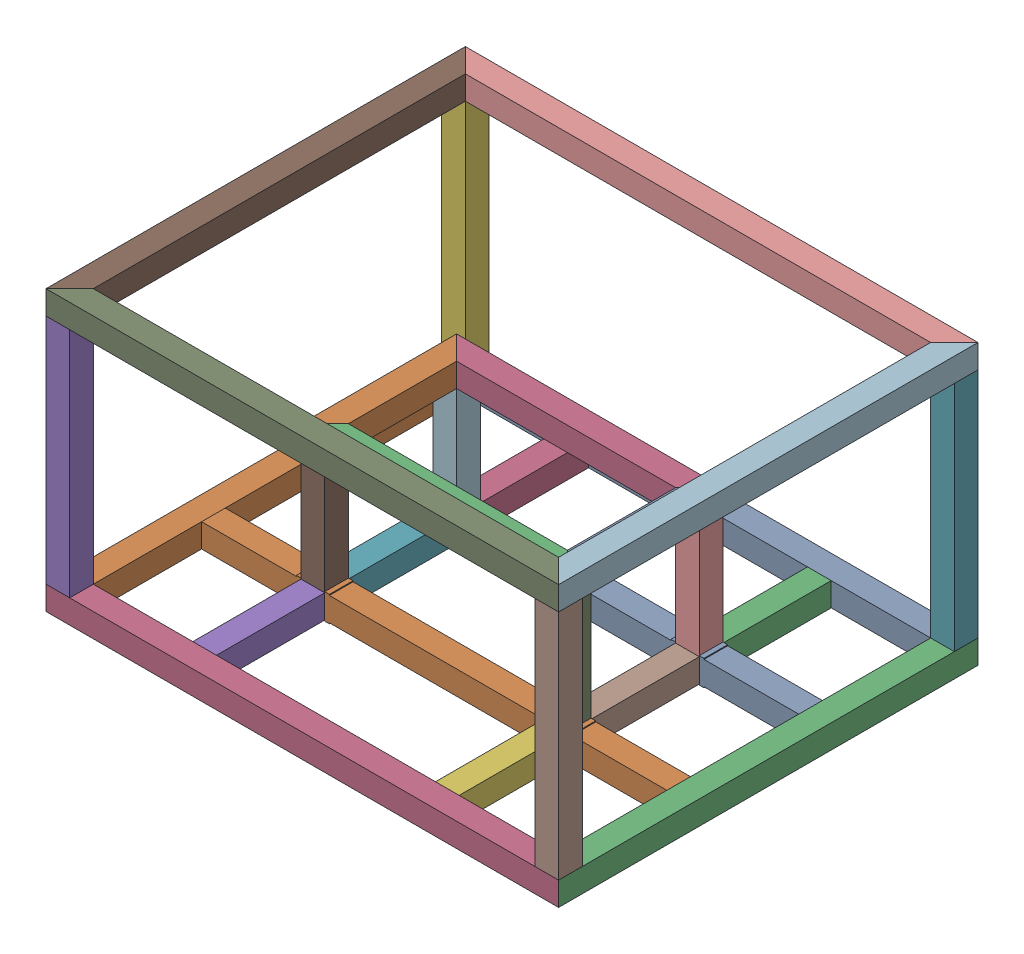
SolidWorks assembly AGV_ensamble, configuration Predeterminado. Lengths in mm.
Overall size (550 301 450).
28 component instances, 9 part files, 72 mates.
Components (placement in the parent):
- perfil_angulo45_550-2: perfil_angulo45_550 [Predeterminado] x (-1 0 0) z (0 0 -1) size (550 25.4 25.4)
- perfil_angulo45_450-1: perfil_angulo45_450 [Predeterminado] at (-550 0 0) x (0 0 1) z (-1 0 0) size (450 25.4 25.4)
- perfil_angulo45_450-2: perfil_angulo45_450 [Predeterminado] at (0 0 450) x (0 0 -1) z (1 0 0) size (450 25.4 25.4)
- perfil_angulo45_550-3: perfil_angulo45_550 [Predeterminado] at (-550 0 450) size (550 25.4 25.4)
- perfil_sencillo_250-1: perfil_sencillo_250 [Predeterminado] at (-524.6 25.4 450) x (0 0 -1) z (1 0 0) size (25.4 249.2 25.4)
- perfil_sencillo_250-2: perfil_sencillo_250 [Predeterminado] at (-524.6 25.4 25.4) x (0 0 -1) z (1 0 0) size (25.4 249.2 25.4)
- perfil_sencillo_250-3: perfil_sencillo_250 [Predeterminado] at (0 25.4 25.4) x (0 0 -1) z (1 0 0) size (25.4 249.2 25.4)
- perfil_sencillo_250-4: perfil_sencillo_250 [Predeterminado] at (-25.4 25.4 450) size (25.4 249.2 25.4)
- perfil_angulo45_550-4: perfil_angulo45_550 [Predeterminado] at (-550 274.6 450) size (550 25.4 25.4)
- perfil_angulo45_550-5: perfil_angulo45_550 [Predeterminado] at (-550 300 0) x (1 0 0) z (0 0 -1) size (550 25.4 25.4)
- perfil_angulo45_450-3: perfil_angulo45_450 [Predeterminado] at (-550 300 450) x (0 0 -1) z (-1 0 0) size (450 25.4 25.4)
- perfil_angulo45_450-4: perfil_angulo45_450 [Predeterminado] at (0 300 0) x (0 0 1) z (1 0 0) size (450 25.4 25.4)
- perfil_sencillo_500-1: perfil_sencillo_500 [Predeterminado] at (-524.6 0 166.93) x (0 0 -1) z (0 -1 0) size (25.4 499.2 27.4)
- perfil_sencillo_500-2: perfil_sencillo_500 [Predeterminado] at (-25.4 25.4 308.47) x (0 0 -1) z (0 1 0) size (25.4 499.2 27.4)
- perfil_sencillo_116-1: perfil_sencillo_116 [Predeterminado] at (-132.1 0 25.4) x (0 1 0) z (1 0 0) size (25.4 116.13 25.4)
- perfil_sencillo_116-2: perfil_sencillo_116 [Predeterminado] at (-417.9 0 25.4) x (1 0 0) z (0 -1 0) size (25.4 116.13 25.4)
- perfil_sencillo_116-4: perfil_sencillo_116 [Predeterminado] at (-417.9 25.4 424.6) x (1 0 0) z (0 1 0) size (25.4 116.13 25.4)
- perfil_sencillo_116-6: perfil_sencillo_116 [Predeterminado] at (-157.5 25.4 424.6) x (1 0 0) z (0 1 0) size (25.4 116.13 25.4)
- perfil_sencillo_11614-1: perfil_sencillo_11614 [Predeterminado] at (-417.9 25.4 283.07) x (1 0 0) z (0 1 0) size (25.4 116.14 25.4)
- perfil_sencillo_11614-2: perfil_sencillo_11614 [Predeterminado] at (-132.1 25.4 283.07) x (0 -1 0) z (1 0 0) size (25.4 116.14 25.4)
- perfil_sencillo_119-1: perfil_sencillo_119 [Predeterminado] at (-132.1 144.4 308.47) x (0 -1 0) z (1 0 0) size (119 25.4 25.4)
- perfil_sencillo_119-2: perfil_sencillo_119 [Predeterminado] at (-132.1 144.4 166.93) x (0 -1 0) z (1 0 0) size (119 25.4 25.4)
- perfil_sencillo_119-3: perfil_sencillo_119 [Predeterminado] at (-417.9 144.4 283.07) x (0 -1 0) z (-1 0 0) size (119 25.4 25.4)
- perfil_sencillo_119-4: perfil_sencillo_119 [Predeterminado] at (-417.9 144.4 141.53) x (0 -1 0) z (-1 0 0) size (119 25.4 25.4)
- perfil_angulo45_166_94-1: perfil_angulo45_166_94 [Predeterminado] at (-157.5 169.8 141.53) x (0 -1 0) z (-1 0 0) size (25.4 166.94 25.4)
- perfil_angulo45_166_94-2: perfil_angulo45_166_94 [Predeterminado] at (-392.5 144.4 141.53) x (0 1 0) z (1 0 0) size (25.4 166.94 25.4)
- perfil_angulo45_285_8-1: perfil_angulo45_285_8 [Predeterminado] at (-417.9 144.4 308.47) size (285.8 25.4 25.4)
- perfil_angulo45_285_8-2: perfil_angulo45_285_8 [Predeterminado] at (-132.1 144.4 141.53) x (-1 0 0) z (0 0 -1) size (285.8 25.4 25.4)
Mates (geometry in assembly coordinates):
- Coincident2: coincident anti-aligned: plane of perfil_angulo45_550-2 through (-550 0 0) normal (-0.707107 0 0.707107); plane of perfil_angulo45_450-1 through (-550 0 0) normal (0.707107 0 -0.707107)
- Coincident3: coincident: point of perfil_angulo45_550-2; unknown of perfil_angulo45_450-1
- Parallel5: parallel anti-aligned: plane of perfil_angulo45_450-1 through (-550 0 450) normal (0.707107 0 0.707107); plane of perfil_angulo45_550-3 through (-550 0 450) normal (-0.707107 0 -0.707107)
- Coincident13: coincident aligned: line of perfil_angulo45_450-1 through (-550 25.4 450) axis (0 -1 0); line of perfil_angulo45_550-3 through (-550 25.4 450) axis (0 -1 0)
- Coincident14: coincident anti-aligned: line of perfil_angulo45_450-1 through (-524.6 25.4 424.6) axis (-0.707107 0 0.707107); line of perfil_angulo45_550-3 through (-550 25.4 450) axis (0.707107 0 -0.707107)
- Coincident15: coincident anti-aligned: line of perfil_angulo45_550-2 through (0 25.4 0) axis (-0.707107 0 0.707107); line of perfil_angulo45_450-2 through (-25.4 25.4 25.4) axis (0.707107 0 -0.707107)
- Parallel6: parallel anti-aligned: plane of perfil_angulo45_550-2 through (0 0 0) normal (0.707107 0 0.707107); plane of perfil_angulo45_450-2 through (0 0 0) normal (-0.707107 0 -0.707107)
- Coincident17: coincident aligned: line of perfil_angulo45_550-2 through (-25.4 0 25.4) axis (0 1 0); line of perfil_angulo45_450-2 through (-25.4 0 25.4) axis (0 1 0)
- Coincident24: coincident aligned: line of perfil_angulo45_550-3 through (-550 25.4 450) axis (1 0 0); line of perfil_sencillo_250-1 through (-550 25.4 450) axis (1 0 0)
- Coincident25: coincident aligned: line of perfil_angulo45_450-1 through (-550 25.4 0) axis (0 0 1); line of perfil_sencillo_250-1 through (-550 25.4 424.6) axis (0 0 1)
- Coincident26: coincident aligned: line of perfil_angulo45_450-2 through (0 25.4 450) axis (0 -1 0); line of perfil_angulo45_550-3 through (0 25.4 450) axis (0 -1 0)
- Coincident27: coincident aligned: line of perfil_angulo45_550-2 through (0 25.4 0) axis (-1 0 0); line of perfil_sencillo_250-2 through (-524.6 25.4 0) axis (-1 0 0)
- Coincident28: coincident aligned: line of perfil_angulo45_450-1 through (-550 25.4 0) axis (0 0 1); line of perfil_sencillo_250-2 through (-550 25.4 0) axis (0 0 1)
- Coincident29: coincident aligned: line of perfil_angulo45_550-2 through (0 25.4 0) axis (-1 0 0); line of perfil_sencillo_250-3 through (0 25.4 0) axis (-1 0 0)
- Coincident30: coincident aligned: line of perfil_angulo45_450-2 through (0 25.4 450) axis (0 0 -1); line of perfil_sencillo_250-3 through (0 25.4 25.4) axis (0 0 -1)
- Coincident31: coincident aligned: line of perfil_angulo45_450-2 through (0 25.4 450) axis (0 0 -1); line of perfil_sencillo_250-4 through (0 25.4 450) axis (0 0 -1)
- Coincident32: coincident aligned: line of perfil_angulo45_550-3 through (-550 25.4 450) axis (1 0 0); line of perfil_sencillo_250-4 through (-25.4 25.4 450) axis (1 0 0)
- Coincident37: coincident: point of perfil_sencillo_250-4; point of perfil_angulo45_450-4
- Coincident38: coincident anti-aligned: line of perfil_sencillo_250-4 through (0 274.6 450) axis (0 0 -1); line of perfil_angulo45_450-4 through (0 274.6 0) axis (0 0 1)
- Coincident39: coincident: point of perfil_sencillo_250-4; point of perfil_angulo45_450-4
- Coincident40: coincident: point of perfil_sencillo_250-1; point of perfil_angulo45_550-4
- Coincident41: coincident: point of perfil_sencillo_250-4; point of perfil_angulo45_550-4
- Coincident42: coincident: point of perfil_sencillo_250-1; point of perfil_angulo45_550-4
- Coincident46: coincident: point of perfil_angulo45_550-5; point of perfil_angulo45_450-4
- Coincident47: coincident anti-aligned: line of perfil_sencillo_250-3 through (0 274.6 0) axis (-1 0 0); line of perfil_angulo45_550-5 through (-550 274.6 0) axis (1 0 0)
- Coincident48: coincident: point of perfil_sencillo_250-3; point of perfil_angulo45_550-5
- Coincident49: coincident: point of perfil_sencillo_250-1; point of perfil_angulo45_450-3
- Coincident50: coincident: point of perfil_angulo45_550-5; point of perfil_angulo45_450-3
- Coincident51: coincident aligned: line of perfil_angulo45_550-5 through (-524.6 300 25.4) axis (0 -1 0); line of perfil_angulo45_450-3 through (-524.6 300 25.4) axis (0 -1 0)
- Coincident55: coincident anti-aligned: line of perfil_angulo45_450-1 through (-524.6 25.4 424.6) axis (0 0 -1); line of perfil_sencillo_500-1 through (-524.6 25.4 141.53) axis (0 0 1)
- Coincident56: coincident aligned: line of perfil_angulo45_450-2 through (-25.4 25.4 25.4) axis (0 0 1); line of perfil_sencillo_500-1 through (-25.4 25.4 141.53) axis (0 0 1)
- Coincident57: coincident aligned: line of perfil_angulo45_450-1 through (-524.6 25.4 424.6) axis (0 0 -1); line of perfil_sencillo_500-2 through (-524.6 25.4 308.47) axis (0 0 -1)
- Coincident58: coincident anti-aligned: line of perfil_angulo45_450-2 through (-25.4 25.4 25.4) axis (0 0 1); line of perfil_sencillo_500-2 through (-25.4 25.4 308.47) axis (0 0 -1)
- Coincident61: coincident anti-aligned: line of perfil_angulo45_550-2 through (-524.6 25.4 25.4) axis (1 0 0); line of perfil_sencillo_116-2 through (-392.5 25.4 25.4) axis (-1 0 0)
- Coincident65: coincident anti-aligned: line of perfil_angulo45_550-2 through (-524.6 25.4 25.4) axis (1 0 0); line of perfil_sencillo_116-1 through (-132.1 25.4 25.4) axis (-1 0 0)
- Coincident66: coincident: unknown of perfil_angulo45_450-2
- Parallel9: parallel: line of perfil_angulo45_550-2 through (-1.2 1.2 1.2) axis (-1 0 0)
- Coincident68: coincident: line of perfil_angulo45_550-2 through (0 0 0) axis (-1 0 0)
- Coincident70: coincident: line of perfil_angulo45_550-3 through (-25.4 0 424.6) axis (-1 0 0)
- Coincident82: coincident anti-aligned: line of perfil_angulo45_550-3 through (-25.4 25.4 424.6) axis (-1 0 0); line of perfil_sencillo_116-4 through (-417.9 25.4 424.6) axis (1 0 0)
- Coincident84: coincident aligned: line of perfil_angulo45_550-3 through (-25.4 0 424.6) axis (-1 0 0); line of perfil_sencillo_116-6 through (-132.1 0 424.6) axis (-1 0 0)
- Coincident86: coincident aligned: line of perfil_sencillo_500-1 through (-25.4 25.4 141.53) axis (-1 0 0); line of perfil_sencillo_116-2 through (-392.5 25.4 141.53) axis (-1 0 0)
- Coincident87: coincident aligned: line of perfil_sencillo_500-1 through (-25.4 25.4 141.53) axis (-1 0 0); line of perfil_sencillo_116-1 through (-132.1 25.4 141.53) axis (-1 0 0)
- Coincident88: coincident aligned: line of perfil_sencillo_500-2 through (-524.6 25.4 308.47) axis (1 0 0); line of perfil_sencillo_116-4 through (-417.9 25.4 308.47) axis (1 0 0)
- Coincident89: coincident aligned: line of perfil_sencillo_500-2 through (-524.6 25.4 308.47) axis (1 0 0); line of perfil_sencillo_116-6 through (-157.5 25.4 308.47) axis (1 0 0)
- Coincident90: coincident aligned: line of perfil_sencillo_500-2 through (-524.6 25.4 283.07) axis (1 0 0); line of perfil_sencillo_11614-1 through (-417.9 25.4 283.07) axis (1 0 0)
- Coincident91: coincident anti-aligned: line of perfil_sencillo_500-1 through (-25.4 25.4 166.93) axis (-1 0 0); line of perfil_sencillo_11614-1 through (-417.9 25.4 166.93) axis (1 0 0)
- Coincident97: coincident aligned: line of perfil_sencillo_500-2 through (-524.6 25.4 283.07) axis (1 0 0); line of perfil_sencillo_11614-2 through (-157.5 25.4 283.07) axis (1 0 0)
- Coincident98: coincident anti-aligned: line of perfil_sencillo_500-1 through (-25.4 25.4 166.93) axis (-1 0 0); line of perfil_sencillo_11614-2 through (-157.5 25.4 166.93) axis (1 0 0)
- Coincident101: coincident: point of perfil_sencillo_500-2; point of perfil_sencillo_116-6
- Coincident102: coincident: point of perfil_sencillo_500-2; point of perfil_sencillo_116-4
- Coincident103: coincident: point of perfil_sencillo_500-2; point of perfil_sencillo_11614-1
- Coincident104: coincident: point of perfil_sencillo_500-1; point of perfil_sencillo_116-2
- Coincident105: coincident: point of perfil_sencillo_500-2; point of perfil_sencillo_11614-2
- Coincident106: coincident: point of perfil_sencillo_500-1; point of perfil_sencillo_116-1
- Coincident139: coincident anti-aligned: plane of perfil_sencillo_500-1 through (-25.4 25.4 141.53) normal (0 1 0); plane of perfil_angulo45_94_6-2 through (-132.1 25.4 141.53) normal (0 -1 0)
- Coincident140: coincident aligned: line of perfil_sencillo_500-1 through (-25.4 25.4 141.53) axis (-1 0 0); line of perfil_angulo45_94_6-2 through (-132.1 25.4 141.53) axis (-1 0 0)
- Coincident141: coincident anti-aligned: line of perfil_sencillo_500-1 through (-157.5 25.4 166.93) axis (0 0 -1); line of perfil_angulo45_94_6-2 through (-157.5 25.4 141.53) axis (0 0 1)
- Coincident142: coincident anti-aligned: line of perfil_sencillo_500-2 through (-127.1 25.4 308.47) axis (1 0 0); line of perfil_sencillo_119-1 through (-132.1 25.4 308.47) axis (-1 0 0)
- Coincident143: coincident anti-aligned: line of perfil_sencillo_500-2 through (-157.5 25.4 308.47) axis (0 0 -1); line of perfil_sencillo_119-1 through (-157.5 25.4 283.07) axis (0 0 1)
- Coincident144: coincident aligned: line of perfil_sencillo_500-2 through (-524.6 25.4 308.47) axis (1 0 0); line of perfil_angulo45_94_6-3 through (-417.9 25.4 308.47) axis (1 0 0)
- Coincident145: coincident anti-aligned: line of perfil_sencillo_500-2 through (-392.5 25.4 283.07) axis (0 0 1); line of perfil_angulo45_94_6-3 through (-392.5 25.4 308.47) axis (0 0 -1)
- Coincident146: coincident anti-aligned: line of perfil_sencillo_500-1 through (-422.9 25.4 166.93) axis (-1 0 0); line of perfil_angulo45_94_6-4 through (-417.9 25.4 166.93) axis (1 0 0)
- Coincident147: coincident anti-aligned: line of perfil_sencillo_500-1 through (-392.5 25.4 141.53) axis (0 0 1); line of perfil_angulo45_94_6-4 through (-392.5 25.4 166.93) axis (0 0 -1)
- Coincident148: coincident: line of perfil_sencillo_119-1 through (-157.5 144.4 308.47) axis (1 0 0); line of perfil_angulo45_285_8-1 through (-417.9 144.4 308.47) axis (1 0 0)
- Coincident149: coincident aligned: line of perfil_sencillo_119-3 through (-417.9 144.4 308.47) axis (0 -1 0); line of perfil_angulo45_285_8-1 through (-417.9 169.8 308.47) axis (0 -1 0)
- Coincident150: coincident: line of perfil_sencillo_119-2 through (-157.5 144.4 141.53) axis (1 0 0); line of perfil_angulo45_285_8-2 through (-132.1 144.4 141.53) axis (-1 0 0)
- Coincident151: coincident aligned: line of perfil_sencillo_119-4 through (-417.9 144.4 141.53) axis (0 -1 0); line of perfil_angulo45_285_8-2 through (-417.9 169.8 141.53) axis (0 -1 0)
- Coincident152: coincident: line of perfil_sencillo_119-1 through (-132.1 144.4 283.07) axis (0 0 1); line of perfil_angulo45_166_94-1 through (-132.1 144.4 308.47) axis (0 0 -1)
- Coincident153: coincident anti-aligned: line of perfil_angulo45_166_94-1 through (-132.1 144.4 141.53) axis (0 1 0); line of perfil_angulo45_285_8-2 through (-132.1 169.8 141.53) axis (0 -1 0)
- Coincident154: coincident: line of perfil_angulo45_166_94-2 through (-417.9 169.8 141.53) axis (0 -1 0); line of perfil_angulo45_285_8-2 through (-417.9 169.8 141.53) axis (0 -1 0)
- Coincident155: coincident anti-aligned: line of perfil_angulo45_166_94-2 through (-392.5 169.8 283.07) axis (-0.707107 0 0.707107); line of perfil_angulo45_285_8-1 through (-417.9 169.8 308.47) axis (0.707107 0 -0.707107)
